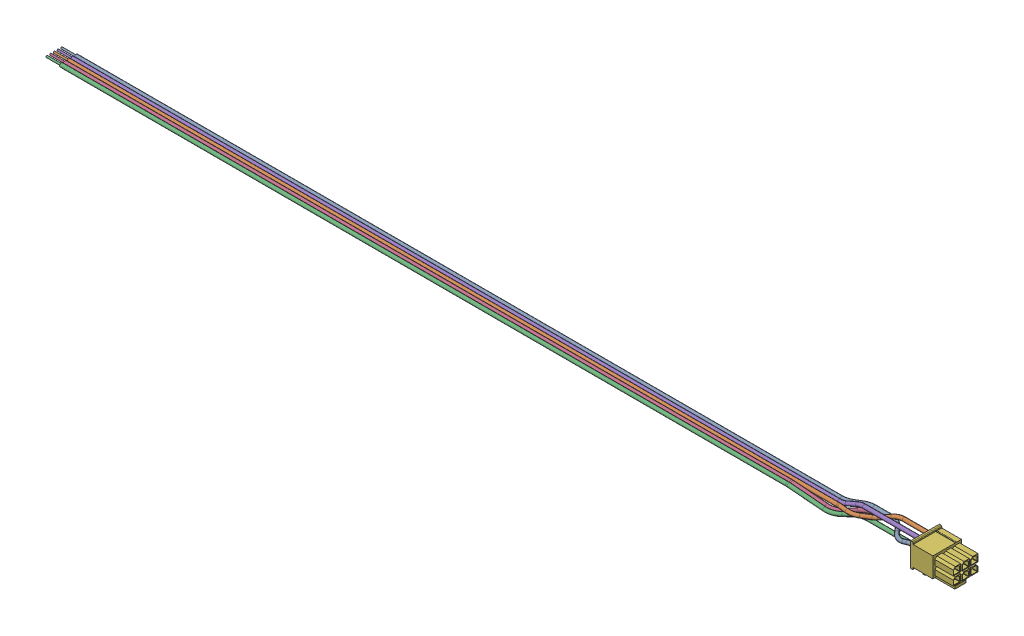
SolidWorks assembly 1393806_ASM, configuration Default. Lengths in mm.
Overall size (311 10.85 10.64).
2 component instances, 2 part files, 0 mates.
Components (placement in the parent):
- 1393805-1: 1393805 [Default] at origin size (301 4.37 9.4)
- 1393804-1: 1393804 [Default] at (296 0 11.43) x (0 0 1) z (0 1 0) size (9.85 14 10.85)
